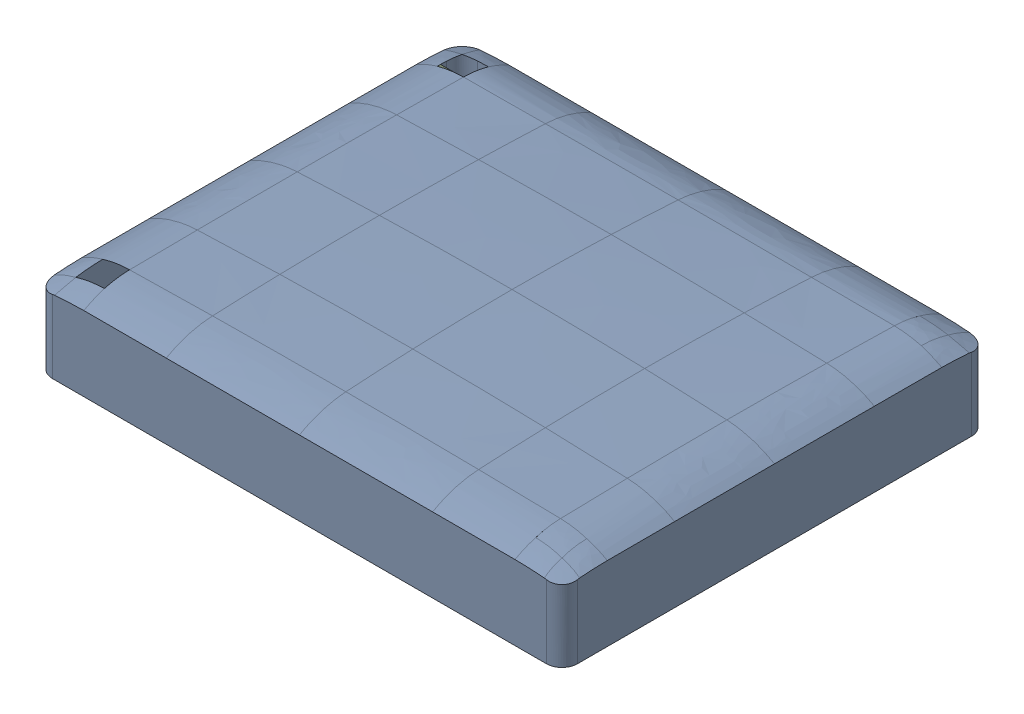
SolidWorks assembly 中间过程, configuration 默认. Lengths in mm.
Overall size (23.8 4.28 19.29).
2 component instances, 2 part files, 4 mates.
Components (placement in the parent):
- Boardholecutout-1: Boardholecutout [默认] at origin size (23.8 4.28 19.29)
- chessboard-1: chessboard [默认] at (-4.7947 21.6 -14.6358) x (1 0 0) z (0 -1 0) size (22.5 16.35 0.4)
Mates (geometry in assembly coordinates):
- 重合1: coordinate: point of Boardholecutout-1
- 平行1: parallel aligned: plane of Boardholecutout-1 through (-11.375 18.2 -9.375) normal (0 -1 0); plane of chessboard-1 through (3.4053 21.2 -6.4358) normal (0 -1 0)
- 距离1: distance = 3 mm aligned: plane of Boardholecutout-1 through (-11.375 18.2 -9.375) normal (0 -1 0); plane of chessboard-1 through (11.6053 21.2 -10.5358) normal (0 -1 0)
- 宽度3: width aligned: plane of Boardholecutout-1 through (-12.075 22 8.375) normal (-1 0 0); plane of chessboard-1 through (11.575 22 8.375) normal (1 0 0); plane of Boardholecutout-1 through (-11.5 21.2 5.78) normal (-1 0 0); plane of chessboard-1 through (11 21.2 5.78) normal (1 0 0)
